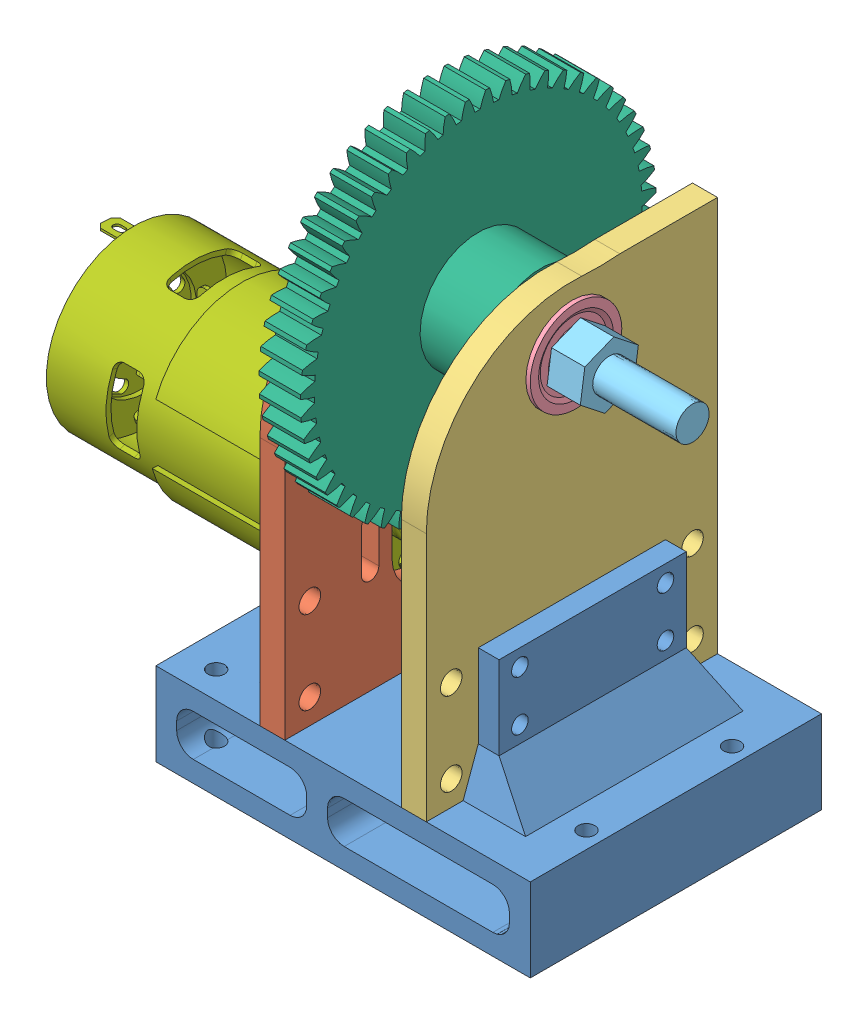
SolidWorks assembly Montaj, configuration Varsayılan. Lengths in mm.
Overall size (147.5 155.92 111.81).
9 component instances, 7 part files, 17 mates.
Components (placement in the parent):
- PART2-1: PART2 [Varsayılan] at (4.5623 5.1675 67.5) size (90 50 70)
- Part1.1-1: Part1.1 [Varsayılan] at (-40.4934 30.8518 68.5896) x (0 0 -1) z (1 0 0) size (70 95 6)
- Part1-1: Part1 [Varsayılan] at (-6.4934 30.8518 68.5896) x (0 0 -1) z (1 0 0) size (70 95 6)
- 8X22X7MM RULMAN-1: 8X22X7MM RULMAN [Varsayılan] at (-5.8934 84.784 90) x (0 -1 0) z (0 0 1) size (22 7 22)
- 8X22X7MM RULMAN-2: 8X22X7MM RULMAN [Varsayılan] at (-40.8934 84.784 90) x (0 -1 0) z (0 0 1) size (22 7 22)
- MİL-1: MİL [Varsayılan] at (-54.4934 80.504 90) x (0 0.734044 -0.679102) z (0 -0.679102 -0.734044) size (13.55 83 15.01)
- spur gear_din-1: spur gear_din [DIN - Spur gear 1.5M 10T 20PA 20FW ---S10A75H50L5N] at (-32.9934 32.2105 88.8281) x (1 0 0) z (0 0.948453 0.316917) size (20 17.23 18)
- spur gear_din-2: spur gear_din [DIN - Spur gear 1.5M 55T 20PA 10FW ---S55B28H25L12N] at (-22.9934 80.504 90) x (-1 0 0) z (0 0.385204 0.922831) size (25 85.46 85.49)
- Motor - RS-775-1: Motor - RS-775 [Default] at (-106.9934 32.2105 88.8281) x (0 0.998076 -0.062008) z (0 0.062008 0.998076) size (44.6 98 43.47)
Mates (geometry in assembly coordinates):
- Çakışık2: coincident anti-aligned: plane of PART2-1 through (-40.4934 0.504 112.5) normal (0 1 0); plane of Part1-1 through (-0.4934 0.504 125) normal (0 -1 0)
- Çakışık4: coincident aligned: plane of PART2-1 through (4.5623 5.1675 125) normal (0 0 1); plane of Part1-1 through (-0.4934 60.504 125) normal (0 0 1)
- Çakışık5: coincident anti-aligned: plane of PART2-1 through (-0.4934 0.504 112.5) normal (-1 0 0); plane of Part1-1 through (-0.4934 60.504 90) normal (1 0 0)
- Eş Merkezli2: concentric anti-aligned: cylinder of Part1-1 through (-0.4934 80.504 90) axis (-1 0 0) radius 11.075; cylinder of 8X22X7MM RULMAN-1 through (2.2693 80.504 90) axis (1 0 0) radius 11
- Çakışık10: coincident aligned: plane of Part1-1 through (-6.4934 60.504 90) normal (-1 0 0); plane of 8X22X7MM RULMAN-1 through (-6.4934 89.504 90) normal (-1 0 0)
- Eş Merkezli3: concentric anti-aligned: cylinder of 8X22X7MM RULMAN-2 through (-32.7307 80.504 90) axis (1 0 0) radius 4; cylinder of MİL-1 through (-34.4934 80.504 90) axis (-1 0 0) radius 4
- Çakışık11: coincident anti-aligned: plane of 8X22X7MM RULMAN-2 through (-34.4934 86.504 90) normal (1 0 0); plane of MİL-1 through (-34.4934 80.504 90) normal (-1 0 0)
- Eş Merkezli4: concentric anti-aligned: cylinder of MİL-1 through (-6.4934 80.504 90) axis (-1 0 0) radius 6; cylinder of spur gear_din-2 through (-47.9935 80.504 90) axis (1 0 0) radius 6
- GearMate2: gear = 10 : 55 mm: line of spur gear_din-2 through (-32.9934 40.1406 75.9159) axis (1 0 0); line of spur gear_din-1 through (-32.9934 32.3224 97.8274) axis (1 0 0)
- Eş Merkezli5: concentric anti-aligned: cylinder of 8X22X7MM RULMAN-1 through (2.2693 80.504 90) axis (1 0 0) radius 4; cylinder of MİL-1 through (28.5066 80.504 90) axis (-1 0 0) radius 4
- Uzaklık1: distance = 1.5 mm anti-aligned: plane of spur gear_din-2 through (-32.9934 80.504 90) normal (-1 0 0); plane of Part1.1-1 through (-34.4934 60.504 90) normal (1 0 0)
- Çakışık13: coincident anti-aligned: plane of PART2-1 through (-40.4934 8.504 112.5) normal (1 0 0); plane of Part1.1-1 through (-40.4934 60.504 90) normal (-1 0 0)
- Çakışık14: coincident anti-aligned: plane of PART2-1 through (-40.4934 0.504 112.5) normal (0 1 0); plane of Part1.1-1 through (-34.4934 0.504 125) normal (0 -1 0)
- Çakışık15: coincident aligned: plane of PART2-1 through (4.5623 5.1675 125) normal (0 0 1); plane of Part1.1-1 through (-34.4934 60.504 125) normal (0 0 1)
- Eş Merkezli6: concentric aligned: cylinder of spur gear_din-1 through (17.0066 32.2105 88.8281) axis (-1 0 0) radius 2.5; cylinder of Motor - RS-775-1 through (-20.9934 32.2105 88.8281) axis (-1 0 0) radius 2.5
- Çakışık18: coincident aligned: plane of spur gear_din-1 through (-32.9934 32.2105 88.8281) normal (-1 0 0); plane of spur gear_din-2 through (-32.9934 80.504 90) normal (-1 0 0)
- Çakışık19: coincident anti-aligned: plane of Part1.1-1 through (-40.4934 60.504 90) normal (-1 0 0); plane of Motor - RS-775-1 through (-40.4934 32.2105 88.8281) normal (1 0 0)
